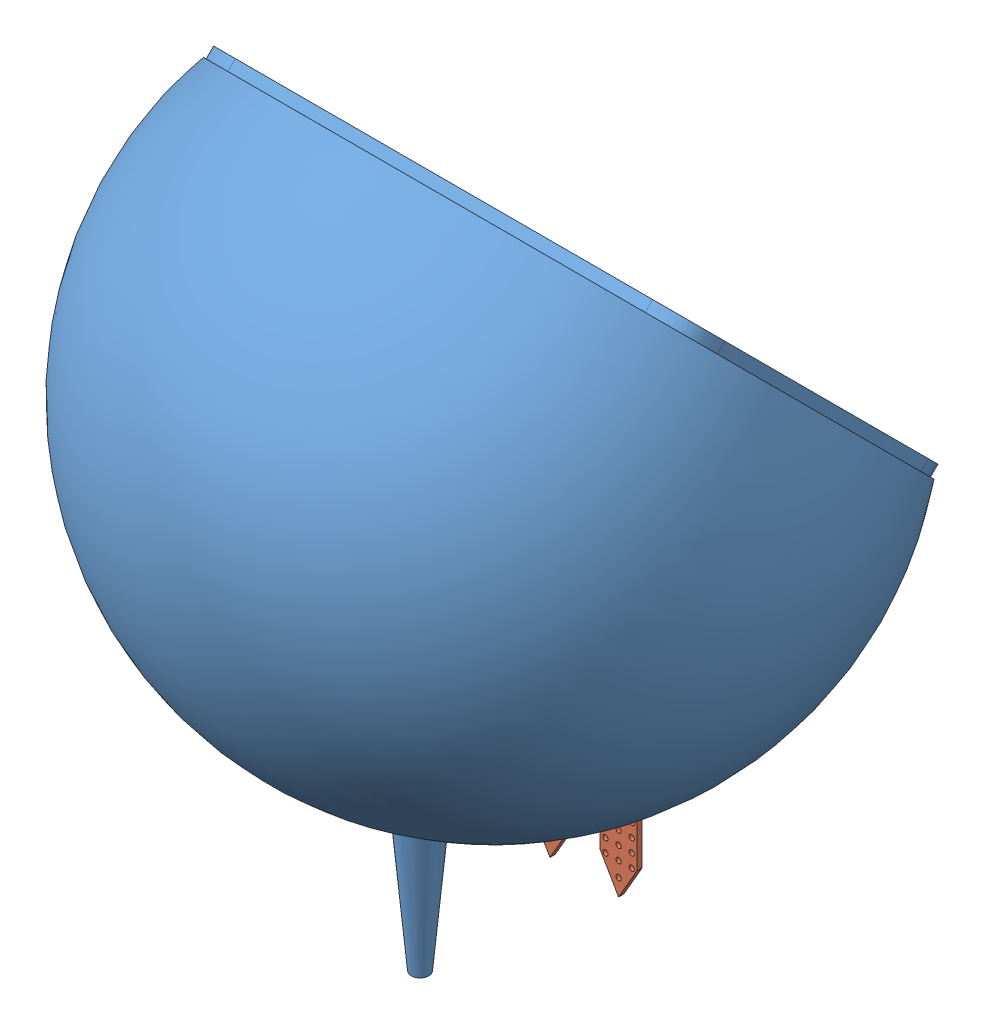
SolidWorks assembly Assemblage1, configuration Défaut. Lengths in mm.
Overall size (623.09 226.77 260.92).
2 component instances, 2 part files, 2 mates.
Components (placement in the parent):
- Pièce3-1: Pièce3 [Défaut] at origin size (623.09 226.77 260.92)
- Soil Humidty sensor-1: Soil Humidty sensor [Default] at (0.2191 -30.1288 -17.4441) x (1 0 0) z (0 -1 0) size (20 3.75 60.7)
Mates (geometry in assembly coordinates):
- Perpendiculaire6: perpendicular: plane of Pièce3-1 through (0 -50 0) normal (0 -1 0); plane of ? through (-8.822 -38.7064 -19.8226) normal (0 0 -1)
- Symétrique1: symmetric: plane of Pièce3-1 through (0 -50 0) normal (0 -1 0); plane of ? through (0.178 -29.8779 -18.8326) normal (0 0 1); plane of ? through (0.178 -29.8779 -18.8326) normal (0 0 1)
